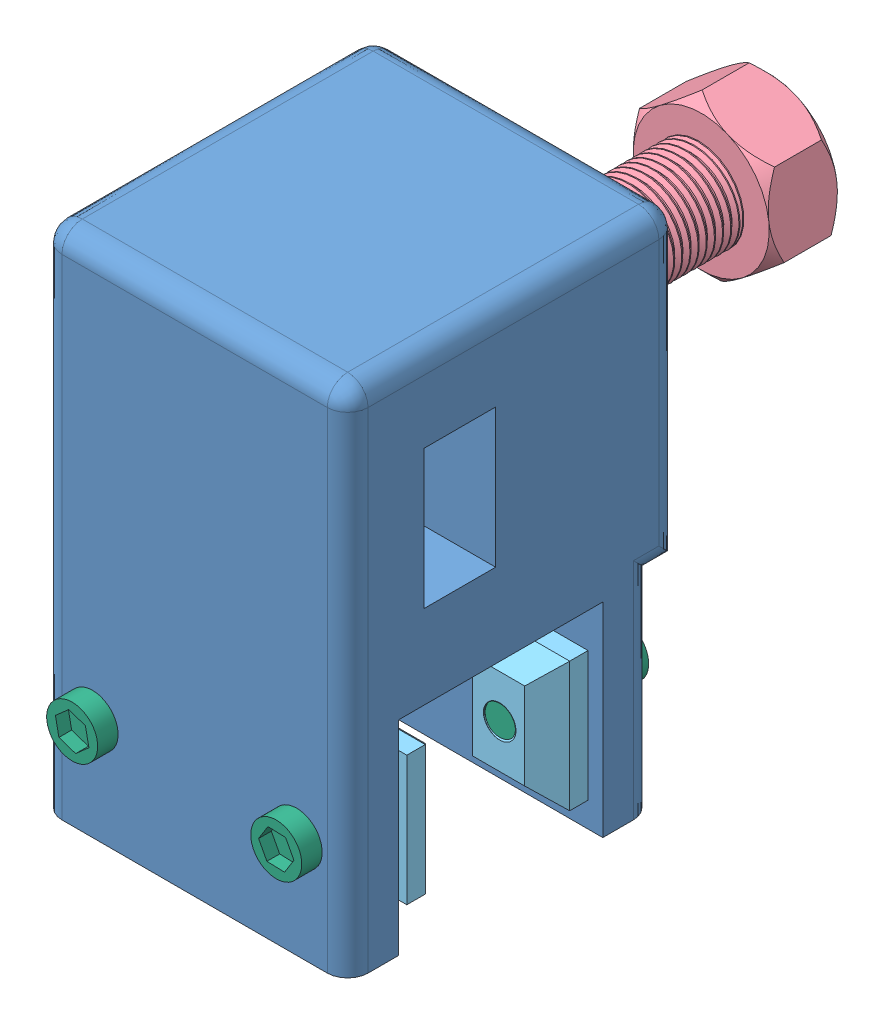
SolidWorks assembly Connector to Diff, configuration Default. Lengths in mm.
Overall size (30 50 58.32).
13 component instances, 7 part files, 24 mates.
Components (placement in the parent):
- Diiferential to body-1: Diiferential to body [Default] at (24.709 27.3558 34.3312) size (30 50 32.5)
- double row cylindrical roller bearing_is-3: double row cylindrical roller bearing_is [IS 6458 DC - 30-9-S] at (24.709 37.3558 22.8312) x (0.2568 -0.966465 0) z (0 0 1) size (24 24 12)
- M8 Nut-1: M8 Nut [Default] at (24.709 37.3558 38.1645) x (0 -1 0) z (0 0 1) size (13.33 16.93 7.25)
- M8 Bolt for differential-1: M8 Bolt for differential [Default] at (24.709 37.3558 -3.6522) x (-0.992433 -0.122788 0) z (0 0 1) size (13.33 16.93 49.27)
- M3 T-nut-1: M3 T-nut [Default] at (34.709 12.3558 25.5257) x (0 0 -1) z (1 0 0) size (4.28 12.7 9.5)
- M3 T-nut-2: M3 T-nut [Default] at (14.709 12.3558 25.6632) x (0 0 -1) z (1 0 0) size (4.28 12.7 9.5)
- M3 T-nut-3: M3 T-nut [Default] at (14.709 12.3558 43.4046) x (0 0 1) z (-1 0 0) size (4.28 12.7 9.5)
- M3 bolt-1: M3 bolt [Default] at (34.709 12.3558 18.5812) x (0.927028 0.374992 0) z (0 0 1) size (5 5 12.17)
- M3 bolt-2: M3 bolt [Default] at (14.709 12.3558 18.5812) x (0.999752 -0.022253 0) z (0 0 1) size (5 5 12.17)
- M3 bolt-3: M3 bolt [Default] at (34.709 12.3558 50.0812) x (-0.848374 0.529398 0) z (0 0 -1) size (5 5 12.17)
- M3 bolt-4: M3 bolt [Default] at (14.709 12.3558 50.0812) x (-0.318543 -0.947908 0) z (0 0 -1) size (5 5 12.17)
- M3 T-nut-4: M3 T-nut [Default] at (34.709 12.3558 43.2854) x (0 0 1) z (-1 0 0) size (4.28 12.7 9.5)
- Washer-1: Washer [Default] at (24.709 37.3558 16.8312) x (0.576118 -0.817367 0) z (0.817367 0.576118 0) size (15.5 0.5 15.5)
Mates (geometry in assembly coordinates):
- Coincident1: coincident: plane of Diiferential to body-1 through (16.909 44.1558 34.8312) normal (0 0 1); plane of M8 Nut-1 through (24.709 37.3558 34.8312) normal (0 0 -1)
- Coincident23: coincident: axis of Diiferential to body-1 through (34.709 12.3558 24.3312) axis (0 0 -1); axis of M3 T-nut-1 through (34.709 12.3558 29.5329) axis (0 0 -1)
- Coincident24: coincident: axis of Diiferential to body-1 through (14.709 12.3558 24.3312) axis (0 0 -1); axis of M3 T-nut-2 through (14.709 12.3558 29.6704) axis (0 0 -1)
- Coincident25: coincident: axis of Diiferential to body-1 through (34.709 12.3558 48.8312) axis (0 0 -1); axis of M3 T-nut-4 through (34.709 12.3558 39.2782) axis (0 0 1)
- Coincident26: coincident: axis of Diiferential to body-1 through (14.709 12.3558 48.8312) axis (0 0 -1); axis of M3 T-nut-3 through (14.709 12.3558 39.3975) axis (0 0 1)
- Coincident27: coincident: axis of Diiferential to body-1 through (34.709 12.3558 24.3312) axis (0 0 -1); axis of M3 bolt-1 through (34.709 12.3558 19.8312) axis (0 0 -1)
- Coincident28: coincident: axis of Diiferential to body-1 through (14.709 12.3558 24.3312) axis (0 0 -1); axis of M3 bolt-2 through (14.709 12.3558 19.8312) axis (0 0 -1)
- Coincident29: coincident: axis of Diiferential to body-1 through (34.709 12.3558 48.8312) axis (0 0 -1); axis of M3 bolt-3 through (34.709 12.3558 48.8312) axis (0 0 1)
- Coincident30: coincident: axis of Diiferential to body-1 through (14.709 12.3558 48.8312) axis (0 0 -1); axis of M3 bolt-4 through (14.709 12.3558 48.8312) axis (0 0 1)
- Parallel10: parallel: plane of Diiferential to body-1 through (39.709 2.3558 49.3312) normal (1 0 0); plane of M3 T-nut-1 through (39.459 12.3558 25.5257) normal (1 0 0)
- Parallel11: parallel: plane of Diiferential to body-1 through (39.709 2.3558 49.3312) normal (1 0 0); plane of M3 T-nut-2 through (19.459 12.3558 25.6632) normal (1 0 0)
- Parallel12: parallel: plane of Diiferential to body-1 through (39.709 2.3558 49.3312) normal (1 0 0); plane of M3 T-nut-4 through (39.459 12.3558 43.2854) normal (1 0 0)
- Parallel13: parallel: plane of Diiferential to body-1 through (39.709 2.3558 49.3312) normal (1 0 0); plane of M3 T-nut-3 through (19.459 12.3558 43.4046) normal (1 0 0)
- Coincident31: coincident: plane of Diiferential to body-1 through (14.709 12.3558 19.8312) normal (0 0 -1); plane of M3 bolt-2 through (14.709 12.3558 19.8312) normal (0 0 1)
- Coincident32: coincident: plane of Diiferential to body-1 through (34.709 12.3558 19.8312) normal (0 0 -1); plane of M3 bolt-1 through (34.709 12.3558 19.8312) normal (0 0 1)
- Coincident33: coincident: plane of Diiferential to body-1 through (34.709 12.3558 48.8312) normal (0 0 1); plane of M3 bolt-3 through (34.709 12.3558 48.8312) normal (0 0 -1)
- Coincident34: coincident: plane of Diiferential to body-1 through (14.709 12.3558 48.8312) normal (0 0 1); plane of M3 bolt-4 through (14.709 12.3558 48.8312) normal (0 0 -1)
- Parallel15: parallel: plane of Diiferential to body-1 through (16.909 30.5558 34.8312) normal (0 1 0); plane of M8 Nut-1 through (20.86 30.6891 41.4978) normal (0 -1 0)
- Lock2: lock: unknown of double row cylindrical roller bearing_is-3; unknown of Washer-1
- Distance1: distance = 16.65 mm: plane of M8 Bolt for differential-1 through (24.709 37.3558 -0.3188) normal (0 0 1); plane of Washer-1 through (24.709 37.3558 16.3312) normal (0 0 -1)
- Coincident35: coincident: axis of double row cylindrical roller bearing_is-3 through (24.709 37.3558 17.1312) axis (0 0 1); axis of M8 Nut-1 through (24.709 37.3558 34.8312) axis (0 0 1)
- Coincident36: coincident: axis of double row cylindrical roller bearing_is-3 through (24.709 37.3558 17.1312) axis (0 0 1); axis of M8 Bolt for differential-1 through (24.709 37.3558 41.7812) axis (0 0 -1)
- Coincident37: coincident: axis of Diiferential to body-1 through (24.709 37.3558 28.8312) axis (0 0 -1); axis of double row cylindrical roller bearing_is-3 through (24.709 37.3558 17.1312) axis (0 0 1)
- Coincident38: coincident: plane of Diiferential to body-1 through (24.709 27.3558 28.8312) normal (0 0 -1); plane of double row cylindrical roller bearing_is-3 through (36.3066 40.4374 28.8312) normal (0 0 1)
